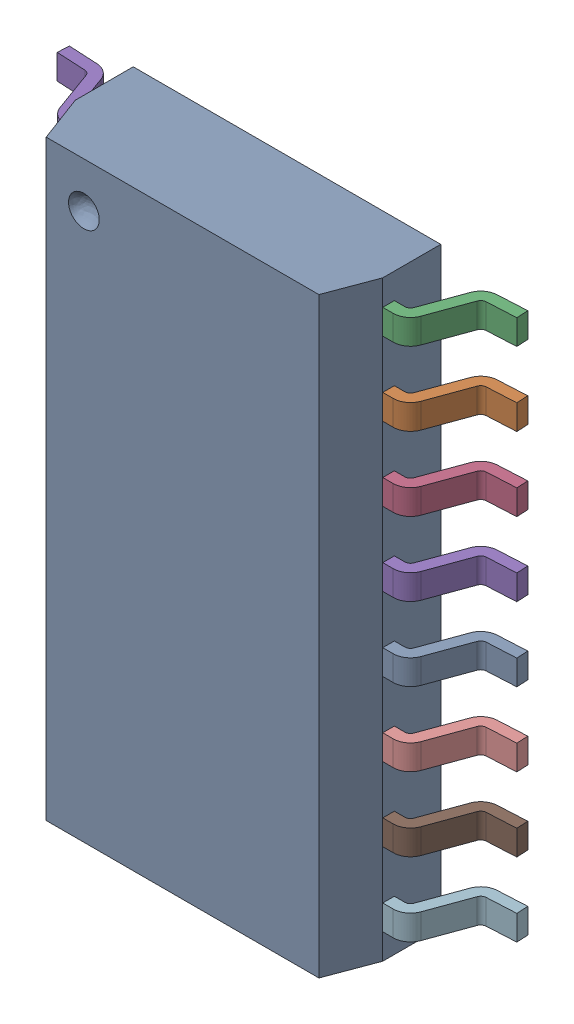
SolidWorks assembly SOP-16, configuration 默认. Lengths in mm.
Overall size (7.92 10.2 2.07).
30 component instances, 2 part files, 0 mates.
Components (placement in the parent):
- User Library-SOP16_208mil (5.3mm)-1: User Library-SOP16_208mil (5.3mm) [默认] x (-1 0 0) z (0 0 1) size (7.92 10.2 2.07)
  - SOP16 Body-1: SOP16 Body [默认] at origin size (5.3 10.2 1.87)
  - Foot SOP16-1: Foot SOP16 [默认] at (3.95 -0.85 -0.1979) x (-1 0 0) z (0 0 1) size (1.31 0.43 1.2)
  - Foot SOP16-2: Foot SOP16 [默认] at (3.95 -2.12 -0.1979) x (-1 0 0) z (0 0 1) size (1.31 0.43 1.2)
  - Foot SOP16-3: Foot SOP16 [默认] at (3.95 -3.39 -0.1979) x (-1 0 0) z (0 0 1) size (1.31 0.43 1.2)
  - Foot SOP16-4: Foot SOP16 [默认] at (3.95 -4.66 -0.1979) x (-1 0 0) z (0 0 1) size (1.31 0.43 1.2)
  - Foot SOP16-5: Foot SOP16 [默认] at (3.95 0.42 -0.1979) x (-1 0 0) z (0 0 1) size (1.31 0.43 1.2)
  - Foot SOP16-6: Foot SOP16 [默认] at (3.95 -0.85 -0.1979) x (-1 0 0) z (0 0 1) size (1.31 0.43 1.2)
  - Foot SOP16-7: Foot SOP16 [默认] at (3.95 -2.12 -0.1979) x (-1 0 0) z (0 0 1) size (1.31 0.43 1.2)
  - Foot SOP16-8: Foot SOP16 [默认] at (3.95 -3.39 -0.1979) x (-1 0 0) z (0 0 1) size (1.31 0.43 1.2)
  - Foot SOP16-9: Foot SOP16 [默认] at (3.95 1.69 -0.1979) x (-1 0 0) z (0 0 1) size (1.31 0.43 1.2)
  - Foot SOP16-10: Foot SOP16 [默认] at (3.95 0.42 -0.1979) x (-1 0 0) z (0 0 1) size (1.31 0.43 1.2)
  - Foot SOP16-11: Foot SOP16 [默认] at (3.95 -0.85 -0.1979) x (-1 0 0) z (0 0 1) size (1.31 0.43 1.2)
  - Foot SOP16-12: Foot SOP16 [默认] at (3.95 -2.12 -0.1979) x (-1 0 0) z (0 0 1) size (1.31 0.43 1.2)
  - Foot SOP16-13: Foot SOP16 [默认] at (3.95 2.96 -0.1979) x (-1 0 0) z (0 0 1) size (1.31 0.43 1.2)
  - Foot SOP16-14: Foot SOP16 [默认] at (3.95 1.69 -0.1979) x (-1 0 0) z (0 0 1) size (1.31 0.43 1.2)
  - Foot SOP16-15: Foot SOP16 [默认] at (3.95 0.42 -0.1979) x (-1 0 0) z (0 0 1) size (1.31 0.43 1.2)
  - Foot SOP16-16: Foot SOP16 [默认] at (3.95 -0.85 -0.1979) x (-1 0 0) z (0 0 1) size (1.31 0.43 1.2)
  - Foot SOP16-17: Foot SOP16 [默认] at (3.95 4.23 -0.1979) x (-1 0 0) z (0 0 1) size (1.31 0.43 1.2)
  - Foot SOP16-18: Foot SOP16 [默认] at (3.95 2.96 -0.1979) x (-1 0 0) z (0 0 1) size (1.31 0.43 1.2)
  - Foot SOP16-19: Foot SOP16 [默认] at (3.95 1.69 -0.1979) x (-1 0 0) z (0 0 1) size (1.31 0.43 1.2)
  - Foot SOP16-20: Foot SOP16 [默认] at (3.95 0.42 -0.1979) x (-1 0 0) z (0 0 1) size (1.31 0.43 1.2)
  - Foot SOP16-21: Foot SOP16 [默认] at (-3.95 2.12 -0.1979) size (1.31 0.43 1.2)
  - Foot SOP16-22: Foot SOP16 [默认] at (-3.95 3.39 -0.1979) size (1.31 0.43 1.2)
  - Foot SOP16-23: Foot SOP16 [默认] at (-3.95 4.66 -0.1979) size (1.31 0.43 1.2)
  - Foot SOP16-24: Foot SOP16 [默认] at (-3.95 0.85 -0.1979) size (1.31 0.43 1.2)
  - Foot SOP16-25: Foot SOP16 [默认] at (-3.95 -2.96 -0.1979) size (1.31 0.43 1.2)
  - Foot SOP16-26: Foot SOP16 [默认] at (-3.95 -4.23 -0.1979) size (1.31 0.43 1.2)
  - Foot SOP16-27: Foot SOP16 [默认] at (-3.95 -1.69 -0.1979) size (1.31 0.43 1.2)
  - Foot SOP16-28: Foot SOP16 [默认] at (-3.95 -0.42 -0.1979) size (1.31 0.43 1.2)
